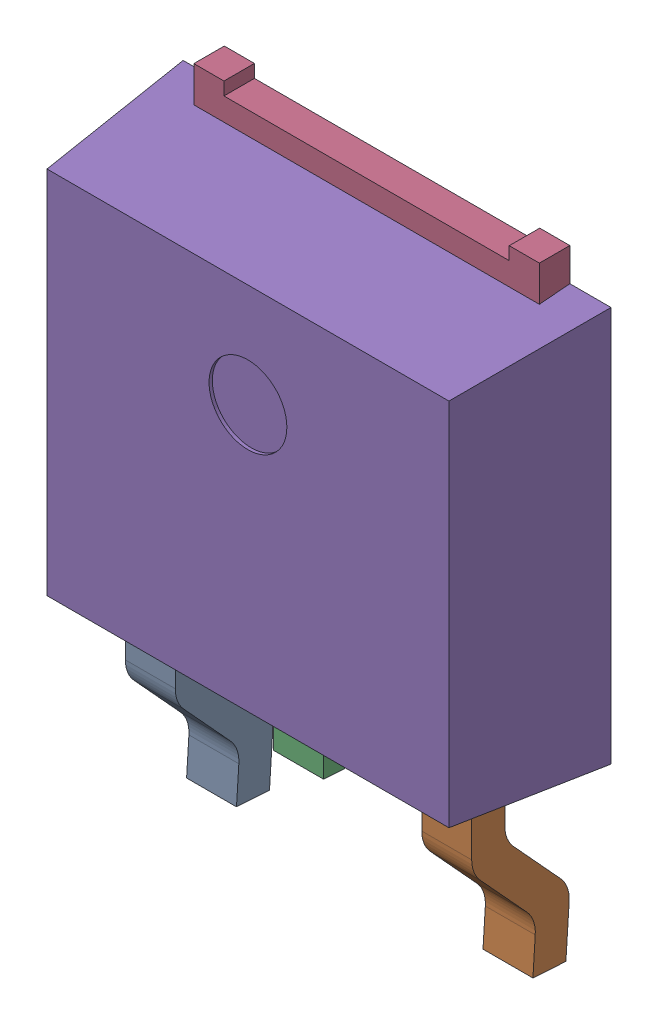
SolidWorks assembly IC22_1.step, configuration Default. Lengths in mm.
Overall size (6.6 9.53 2.3).
3 component instances, 2 part files, 0 mates.
Components (placement in the parent):
- 6348793488_1.step-3: 6348793488_1.step [Default] at (377.958 305.354 0) x (1 0 0) z (0 0 1) size (6.6 9.53 2.3)
  - Linear Pattern 01_1.step-5: Linear Pattern 01_1.step [Default] at origin size (5.34 3.53 1.5)
  - Open CASCADE STEP translator 7.5 5.121.1.2_1.step-5: Open CASCADE STEP translator 7.5 5.121.1.2_1.step [Default] at origin size (6.6 6.61 2.3)
